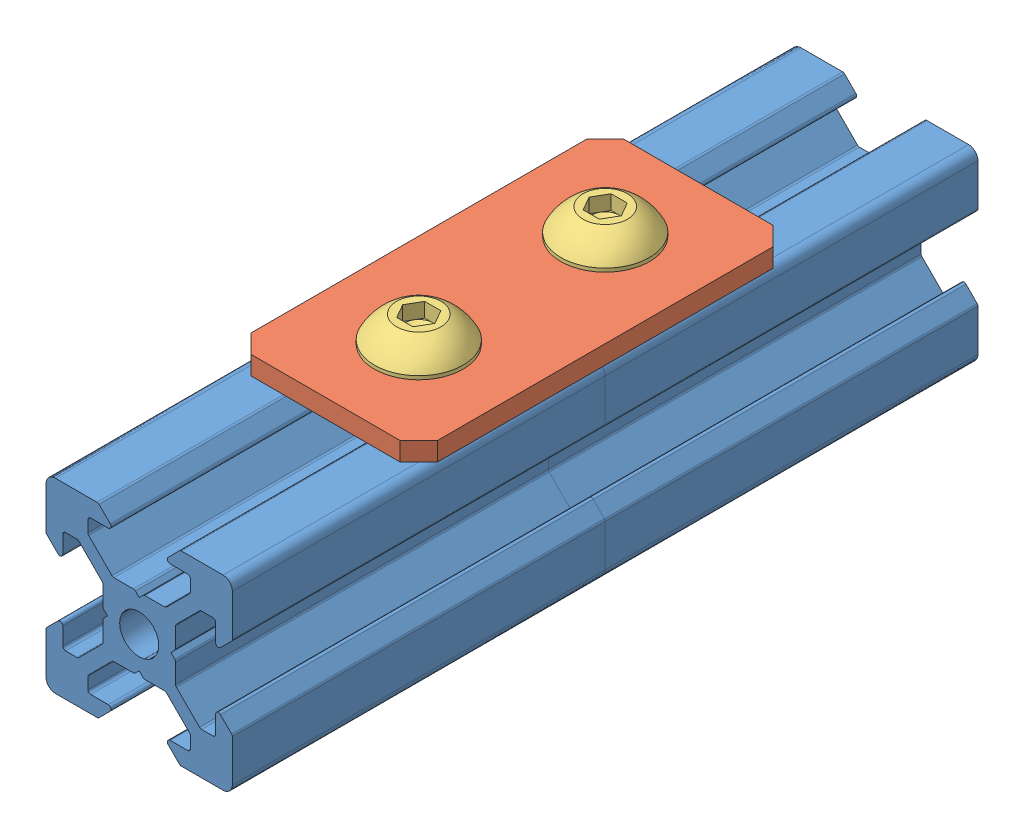
SolidWorks assembly П-Пластина 20 серия 1х2 2отв 20х40х2, configuration По умолчанию. Lengths in mm.
Overall size (20 24.75 80).
5 component instances, 3 part files, 10 mates.
Components (placement in the parent):
- 2020100-1: 2020100 [По умолчанию] at origin size (20 20 40)
- 2020100-2: 2020100 [По умолчанию] at (0 0 -40) size (20 20 40)
- П-Пластина 20 серия 1х2 2отв 20х40х2-1: П-Пластина 20 серия 1х2 2отв 20х40х2 [По умолчанию] at (0 12 0) x (1 0 0) z (0 -1 0) size (20 40 2)
- socket button head screw_iso-1: socket button head screw_iso [ISO 7380 - M5 x 10 - 10N] at (0 14.75 10) x (0 -1 0) z (0 0 1) size (12.75 9.5 9.5)
- socket button head screw_iso-2: socket button head screw_iso [ISO 7380 - M5 x 10 - 10N] at (0 14.75 -10) x (0 -1 0) z (0 0 1) size (12.75 9.5 9.5)
Mates (geometry in assembly coordinates):
- Совпадение1: coincident anti-aligned: plane of 2020100-1 through (0 0 0) normal (0 0 -1); plane of 2020100-2 through (0 0 0) normal (0 0 1)
- Совпадение2: coincident aligned: plane of 2020100-1 through (-10 10 40) normal (0 1 0); plane of 2020100-2 through (-10 10 0) normal (0 1 0)
- Совпадение3: coincident aligned: plane of 2020100-1 through (10 10 40) normal (1 0 0); plane of 2020100-2 through (10 10 0) normal (1 0 0)
- Совпадение4: coincident anti-aligned: plane of 2020100-1 through (-10 10 40) normal (0 1 0); plane of П-Пластина 20 серия 1х2 2отв 20х40х2-1 through (0 10 0) normal (0 -1 0)
- Совпадение5: coincident aligned: plane of 2020100-1 through (10 10 40) normal (1 0 0); plane of П-Пластина 20 серия 1х2 2отв 20х40х2-1 through (10 10 -20) normal (1 0 0)
- Расстояние1: distance = 20 mm aligned: plane of П-Пластина 20 серия 1х2 2отв 20х40х2-1 through (-10 10 20) normal (0 0 1); plane of 2020100-1 through (0 0 40) normal (0 0 1)
- Концентричный1: concentric anti-aligned: cylinder of П-Пластина 20 серия 1х2 2отв 20х40х2-1 through (0 10 10) axis (0 -1 0) radius 2.75; cylinder of socket button head screw_iso-1 through (0 14.75 10) axis (0 1 0) radius 4.75
- Совпадение7: coincident anti-aligned: plane of П-Пластина 20 серия 1х2 2отв 20х40х2-1 through (0 12 0) normal (0 1 0); plane of socket button head screw_iso-1 through (2.5 12 10) normal (0 -1 0)
- Концентричный2: concentric anti-aligned: cylinder of П-Пластина 20 серия 1х2 2отв 20х40х2-1 through (0 10 -10) axis (0 -1 0) radius 2.75; cylinder of socket button head screw_iso-2 through (0 14.75 -10) axis (0 1 0) radius 4.75
- Совпадение8: coincident anti-aligned: plane of П-Пластина 20 серия 1х2 2отв 20х40х2-1 through (0 12 0) normal (0 1 0); plane of socket button head screw_iso-2 through (2.5 12 -10) normal (0 -1 0)
